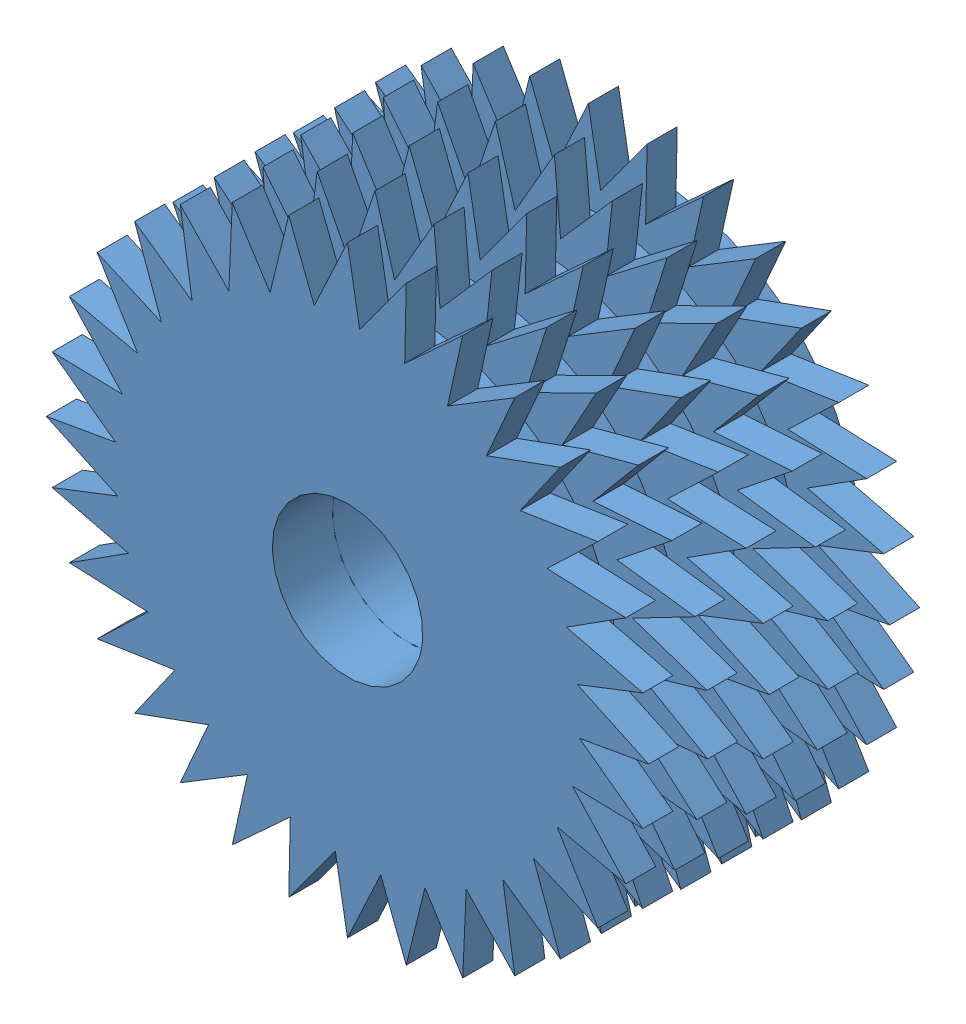
SolidWorks assembly kısa_sılındır, configuration Varsayılan. Lengths in mm.
Overall size (23.52 23.52 10).
5 component instances, 1 part files, 17 mates.
Components (placement in the parent):
- Parça1-3: Parça1 [Varsayılan] at (13.9957 5.0507 15.6098) size (20 20 2)
- Parça1-4: Parça1 [Varsayılan] at (13.9957 5.0507 11.6098) x (0.980785 0.19509 0) z (0 0 1) size (20 20 2)
- Parça1-5: Parça1 [Varsayılan] at (13.9957 5.0507 13.6098) x (0.994056 0.108867 0) z (0 0 1) size (20 20 2)
- Parça1-6: Parça1 [Varsayılan] at (13.9957 5.0507 17.6098) x (0.996195 -0.087156 0) z (0 0 1) size (20 20 2)
- Parça1-7: Parça1 [Varsayılan] at (13.9957 5.0507 19.6098) x (0.980785 -0.19509 0) z (0 0 1) size (20 20 2)
Mates (geometry in assembly coordinates):
- Eş Merkezli1: concentric: 
- Uzaklık1: distance: 
- Teğet1: tangent: 
- Teğet2: tangent: 
- GearMate1: gear: 
- Eş Merkezli2: concentric: Parça1-3, Parça1-4
- Eş Merkezli3: concentric: Parça1-4, Parça1-5
- Eş Merkezli4: concentric: Parça1-3, Parça1-6
- Eş Merkezli5: concentric: Parça1-6, Parça1-7
- Çakışık1: coincident: Parça1-4, Parça1-5
- Çakışık2: coincident: Parça1-3, Parça1-5
- Çakışık3: coincident: Parça1-3, Parça1-6
- Çakışık4: coincident: Parça1-6, Parça1-7
- Açı1: planar angle: Parça1-4, Parça1-5
- Açı2: planar angle: Parça1-5, Parça1-3
- Açı3: planar angle: Parça1-3, Parça1-6
- Açı4: planar angle: Parça1-6, Parça1-7
